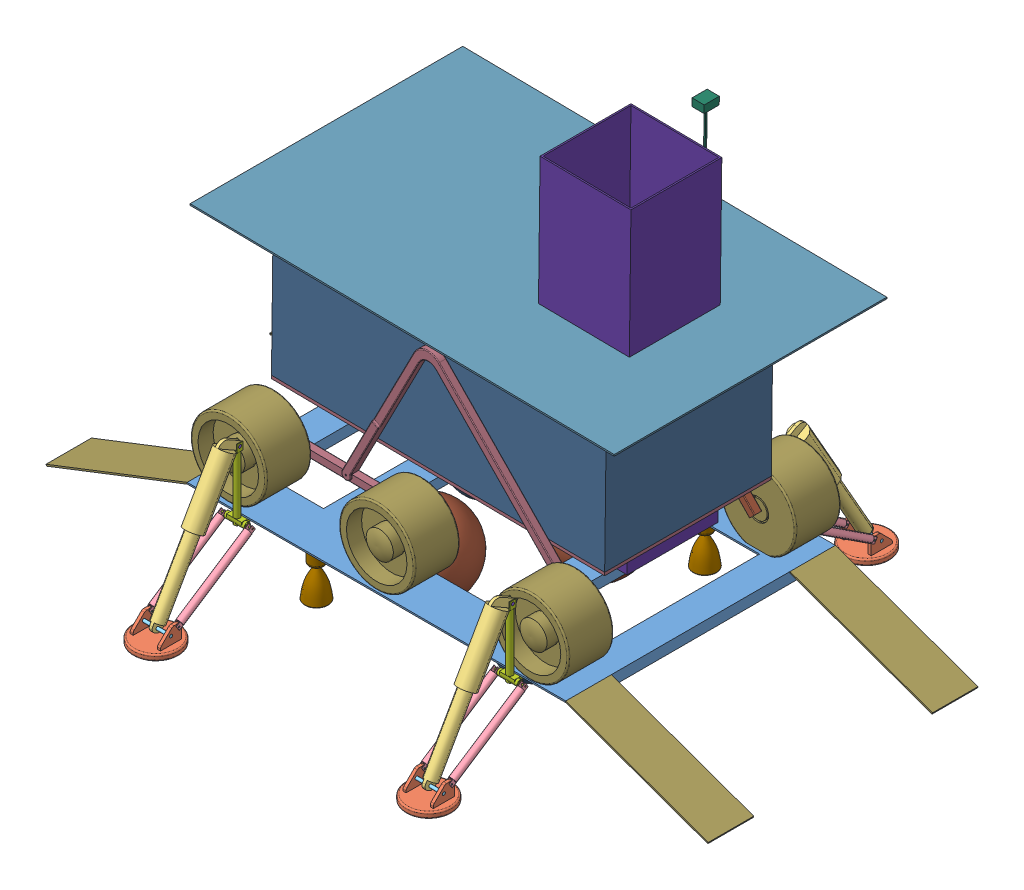
SolidWorks assembly Rover Lander assem, configuration Default. Lengths in mm.
Overall size (4376.53 3029.6 3190.9).
97 component instances, 36 part files, 4 mates.
Components (placement in the parent):
- lander_base_assem-1: lander_base_assem [Default] at (-53.6849 8.2156 22.7472) size (4376.53 1074.03 3190.9)
  - Lander base-1: Lander base [Default] at (714.6592 -461.0878 -63.8597) size (2500 70 1780)
  - leg_aluminum_rev-1: leg_aluminum_rev [Default] at (365.8635 -910.6524 482.3383) x (0 0.000985 1) z (-1 0 0) size (725.04 964.3 300)
    - base_leg-1: base_leg [Default] at (9.2435 -7.9699 0.537) size (300 140 300)
    - Main_leg-1: Main_leg [Default] at (-240.1972 521.872 0.537) x (0 0 -1) z (0.869495 0.493942 0) size (120 996.55 163.86)
    - Support_leg-1: Support_leg [Default] at (-74.206 133.9648 -89.463) x (0 0 -1) z (0.548366 0.836238 0) size (45 600 45)
    - leg_pin-1: leg_pin [Default] at (9.2435 82.777 -99.463) x (0 0 1) z (-0.667547 0.744568 0) size (200 20 20)
    - Support_leg-2: Support_leg [Default] at (-74.206 133.9648 90.537) x (0 0 -1) z (0.548366 0.836238 0) size (45 600 45)
    - leg_support_pin-1: leg_support_pin [Default] at (-40.7565 112.0301 -76.463) x (0 0 -1) z (1 0 0) size (26 10 10)
    - leg_support_pin-2: leg_support_pin [Default] at (-40.7565 112.0301 103.537) x (0 0 -1) z (1 0 0) size (26 10 10)
    - leg_joiner-1: leg_joiner [Default] at (-525.7944 410.0826 0.537) x (1 -0.000985 0) z (0 0 1) size (60 470.09 206)
    - leg_joiner_pin-1: leg_joiner_pin [Default] at (-525.3511 860.1724 -19.463) size (20 20 40)
  - leg_aluminum_rev-2: leg_aluminum_rev [Default] at (364.7896 -910.6524 -2390.0576) x (0 0.000985 -1) z (1 0 0) size (725.04 964.3 300)
    - base_leg-1: base_leg [Default] at (9.2435 -7.9699 0.537) size (300 140 300)
    - Main_leg-1: Main_leg [Default] at (-240.1972 521.872 0.537) x (0 0 -1) z (0.869495 0.493942 0) size (120 996.55 163.86)
    - Support_leg-1: Support_leg [Default] at (-74.206 133.9648 -89.463) x (0 0 -1) z (0.548366 0.836238 0) size (45 600 45)
    - leg_pin-1: leg_pin [Default] at (9.2435 82.777 -99.463) x (0 0 1) z (-0.667547 0.744568 0) size (200 20 20)
    - Support_leg-2: Support_leg [Default] at (-74.206 133.9648 90.537) x (0 0 -1) z (0.548366 0.836238 0) size (45 600 45)
    - leg_support_pin-1: leg_support_pin [Default] at (-40.7565 112.0301 -76.463) x (0 0 -1) z (1 0 0) size (26 10 10)
    - leg_support_pin-2: leg_support_pin [Default] at (-40.7565 112.0301 103.537) x (0 0 -1) z (1 0 0) size (26 10 10)
    - leg_joiner-1: leg_joiner [Default] at (-525.7944 410.0826 0.537) x (1 -0.000985 0) z (0 0 1) size (60 470.09 206)
    - leg_joiner_pin-1: leg_joiner_pin [Default] at (-525.3511 860.1724 -19.463) size (20 20 40)
  - leg_aluminum_rev-3: leg_aluminum_rev [Default] at (-1436.5452 -910.6524 -2390.0576) x (0 0.000985 -1) z (1 0 0) size (725.04 964.3 300)
    - base_leg-1: base_leg [Default] at (9.2435 -7.9699 0.537) size (300 140 300)
    - Main_leg-1: Main_leg [Default] at (-240.1972 521.872 0.537) x (0 0 -1) z (0.869495 0.493942 0) size (120 996.55 163.86)
    - Support_leg-1: Support_leg [Default] at (-74.206 133.9648 -89.463) x (0 0 -1) z (0.548366 0.836238 0) size (45 600 45)
    - leg_pin-1: leg_pin [Default] at (9.2435 82.777 -99.463) x (0 0 1) z (-0.667547 0.744568 0) size (200 20 20)
    - Support_leg-2: Support_leg [Default] at (-74.206 133.9648 90.537) x (0 0 -1) z (0.548366 0.836238 0) size (45 600 45)
    - leg_support_pin-1: leg_support_pin [Default] at (-40.7565 112.0301 -76.463) x (0 0 -1) z (1 0 0) size (26 10 10)
    - leg_support_pin-2: leg_support_pin [Default] at (-40.7565 112.0301 103.537) x (0 0 -1) z (1 0 0) size (26 10 10)
    - leg_joiner-1: leg_joiner [Default] at (-525.7944 410.0826 0.537) x (1 -0.000985 0) z (0 0 1) size (60 470.09 206)
    - leg_joiner_pin-1: leg_joiner_pin [Default] at (-525.3511 860.1724 -19.463) size (20 20 40)
  - leg_aluminum_rev-4: leg_aluminum_rev [Default] at (-1435.4713 -910.6524 482.3383) x (0 0.000985 1) z (-1 0 0) size (725.04 964.3 300)
    - base_leg-1: base_leg [Default] at (9.2435 -7.9699 0.537) size (300 140 300)
    - Main_leg-1: Main_leg [Default] at (-240.1972 521.872 0.537) x (0 0 -1) z (0.869495 0.493942 0) size (120 996.55 163.86)
    - Support_leg-1: Support_leg [Default] at (-74.206 133.9648 -89.463) x (0 0 -1) z (0.548366 0.836238 0) size (45 600 45)
    - leg_pin-1: leg_pin [Default] at (9.2435 82.777 -99.463) x (0 0 1) z (-0.667547 0.744568 0) size (200 20 20)
    - Support_leg-2: Support_leg [Default] at (-74.206 133.9648 90.537) x (0 0 -1) z (0.548366 0.836238 0) size (45 600 45)
    - leg_support_pin-1: leg_support_pin [Default] at (-40.7565 112.0301 -76.463) x (0 0 -1) z (1 0 0) size (26 10 10)
    - leg_support_pin-2: leg_support_pin [Default] at (-40.7565 112.0301 103.537) x (0 0 -1) z (1 0 0) size (26 10 10)
    - leg_joiner-1: leg_joiner [Default] at (-525.7944 410.0826 0.537) x (1 -0.000985 0) z (0 0 1) size (60 470.09 206)
    - leg_joiner_pin-1: leg_joiner_pin [Default] at (-525.3511 860.1724 -19.463) size (20 20 40)
  - MR_80b-1: MR_80b [Default] at (-1081.6322 -841.0878 -214.0715) size (153.97 380 153.97)
  - MR_80b-2: MR_80b [Default] at (16.7233 -838.4394 -1679.7382) x (0.999992 0 0.004071) z (-0.004071 0 0.999992) size (153.97 380 153.97)
  - Helium_tank-1: Helium_tank [Default] at (203.1711 -638.5192 -541.9795) x (0.94256 0.329358 0.055716) z (0.325345 -0.942975 0.070353) size (400 400 400)
  - Helium_tank-2: Helium_tank [Default] at (-953.3371 -635.4687 -1361.8199) x (0.977489 0.124684 0.170201) z (-0.107578 -0.399417 0.910436) size (400 400 400)
  - Hydrazine_tank-1: Hydrazine_tank [Default] at (-643.5463 -334.2768 -539.5578) x (0.363071 0.900077 0.240916) z (0.071543 0.230867 -0.970352) size (550 550 550)
  - Hydrazine_tank-2: Hydrazine_tank [Default] at (-75.2899 -529.4709 -1409.1331) x (0.901296 0.217178 -0.374832) z (0.418463 -0.660267 0.623647) size (550 550 550)
  - ramp-1: ramp [Default] at (-1781.7966 -460.4387 -1543.8597) x (0.935086 0.354421 0) z (0 0 1) size (1000 10 300)
  - ramp-2: ramp [Default] at (-1781.7155 -460.4076 -63.8597) x (0.931973 0.362527 0) z (0 0 1) size (1000 10 300)
  - ramp-3: ramp [Default] at (1652.7267 -797.6846 -1543.8597) x (0.941439 -0.337182 0) z (0 0 1) size (1000 10 300)
  - ramp-4: ramp [Default] at (1652.3714 -798.6446 -63.8597) x (0.941094 -0.338146 0) z (0 0 1) size (1000 10 300)
- layout_Assem_with_cover-1: layout_Assem_with_cover [Default] at (-567.9998 65.7276 -953.5275) x (0.999924 -0.012312 0) z (0 0 1) size (2907.8 2551.43 1996.55)
  - Rover_base-1: Rover_base [Default] at (-1064.6676 -0.8898 562.4151) size (2200 20 1100)
  - Neutron_spectrometer-1: Neutron_spectrometer [Default] at (-926.7762 19.1102 412.2415) size (300 57 300)
  - Neutron_spectrometer_electronics-1: Neutron_spectrometer_electronics [Default] at (-664.5809 19.1102 526.5713) size (180 30 130)
  - gc-1: gc [Default] at (-1085.6976 19.1102 139.436) size (100 80 100)
  - svr_box-1: svr_box [Default] at (435.3324 -172.8625 312.4151) size (600 2100 600)
  - xrf-1: xrf [Default] at (-1008.6936 19.1102 -66.8918) size (80 90 80)
  - geotechnical_exp-1: geotechnical_exp [Default] at (118.8439 19.1102 479.7148) x (0.999975 0 -0.007135) z (0.007135 0 0.999975) size (130 30 130)
  - penetrometer_3-1: penetrometer_3 [Default] at (989.1282 19.1102 -518.5473) x (-0.60186 0 0.798602) z (-0.798602 0 -0.60186) size (20 40 20)
  - penetrometer_3-2: penetrometer_3 [Default] at (934.1975 19.1102 -522.9905) size (20 40 20)
  - penetrometer_3-3: penetrometer_3 [Default] at (890.3988 19.1102 -523.0172) x (0.957231 0 -0.289323) z (0.289323 0 0.957231) size (20 40 20)
  - power-1: power [Default] at (-535.812 19.1102 343.3407) size (180 90 96)
  - geotechnical_exp_vane-1: geotechnical_exp_vane [Default] at (965.2252 19.1102 444.9326) size (220 40 220)
  - Magnents-1: Magnents [Default] at (-1020.4169 -10.8898 98.2252) size (45 10 45)
  - Becon-1: Becon [Default] at (656.9367 19.1102 515.9957) size (80 90 100)
  - Belly Cam-1: Belly Cam [Default] at (-660.0101 -90.1314 99.1462) size (150 100 150)
  - power_tank-1: power_tank [Default] at (-887.862 555.3324 -63.369) x (-0.812429 0.027314 0.58242) z (0.582091 -0.01957 0.812888) size (1560.46 846.95 1367.46)
    - power_tank_10-1: power_tank_10 [Default] at (-67.1815 281.3265 414.5148) size (500 500 500)
    - power_tank_10-2: power_tank_10 [Default] at (-251.8267 476.4977 723.0274) x (0.786037 -0.315714 0.53148) z (0.083274 0.905991 0.415025) size (500 500 500)
    - power_tank_10-3: power_tank_10 [Default] at (-733.4982 325.3571 380.2859) x (0.665484 -0.133715 0.734337) z (-0.678573 0.301428 0.669836) size (500 500 500)
    - power_tank_10-4: power_tank_10 [Default] at (-1034.3616 424.6302 664.9742) x (0.724325 0.588989 -0.358392) z (-0.233278 0.698521 0.676499) size (500 500 500)
    - power_tank_10-5: power_tank_10 [Default] at (-695.3433 297.5492 1147.5051) x (0.994968 0.097333 0.023775) z (-0.042044 0.190197 0.980845) size (500 500 500)
  - Tank_seperator_plate-1: Tank_seperator_plate [Default] at (435.3324 529.1102 512.4151) size (1500 10 1000)
  - power_tank-3: power_tank [Default] at (-887.862 502.888 93.4377) x (-0.812429 -0.027314 -0.58242) z (0.582091 0.01957 -0.812888) size (1560.46 846.95 1367.46)
    - power_tank_10-1: power_tank_10 [Default] at (-67.1815 281.3265 414.5148) size (500 500 500)
    - power_tank_10-2: power_tank_10 [Default] at (-251.8267 476.4977 723.0274) x (0.786037 -0.315714 0.53148) z (0.083274 0.905991 0.415025) size (500 500 500)
    - power_tank_10-3: power_tank_10 [Default] at (-733.4982 325.3571 380.2859) x (0.665484 -0.133715 0.734337) z (-0.678573 0.301428 0.669836) size (500 500 500)
    - power_tank_10-4: power_tank_10 [Default] at (-1034.3616 424.6302 664.9742) x (0.724325 0.588989 -0.358392) z (-0.233278 0.698521 0.676499) size (500 500 500)
    - power_tank_10-5: power_tank_10 [Default] at (-695.3433 297.5492 1147.5051) x (0.994968 0.097333 0.023775) z (-0.042044 0.190197 0.980845) size (500 500 500)
  - Rover_base_cover-1: Rover_base_cover [Default] at (1135.3324 1069.1102 -537.5849) x (1 0 0) z (0 0 -1) size (2200 1050 1100)
  - left_mobiiity_assemSLDASM-1: left_mobiiity_assemSLDASM [Default] at (483.248 -113.7012 -588.2789) x (-1 0 0) z (0 0 -1) size (2699.35 1341.14 400.39)
    - Suspension arms-1: Suspension arms [Default] at (-510.2208 -182.1885 -50.694) size (2035.36 1012.73 130)
    - wheel-1: wheel [Default] at (-515.577 -152.6706 299.306) x (-0.792605 -0.609735 0) z (0 0 -1) size (500 500 300.39)
    - wheel-2: wheel [Default] at (1479.7792 -157.1885 299.306) x (-0.72713 -0.6865 0) z (0 0 -1) size (500 500 300.39)
    - wheel-3: wheel [Default] at (499.7792 -157.1885 299.306) x (-0.949229 -0.314586 0) z (0 0 -1) size (500 500 300.39)
  - right_mobiiity_assemSLDASM-1: right_mobiiity_assemSLDASM [Default] at (657.788 -311.6325 815.2315) x (-1 0 0) z (0 0 -1) size (2495.36 1237.73 400.39)
    - Suspension arms_mirror-1: Suspension arms_mirror [Default] at (-335.6808 35.7938 152.8164) size (2035.36 1012.73 130)
    - wheel-1: wheel [Default] at (1654.3192 60.7938 -97.1836) size (500 500 300.39)
    - wheel-2: wheel [Default] at (-341.0371 65.3118 -97.1836) size (500 500 300.39)
    - wheel-3: wheel [Default] at (674.3192 60.7938 -97.1836) size (500 500 300.39)
  - solar cell-1: solar cell [Default] at (-1264.6676 1069.1102 -887.5849) x (-1 0 0) z (0 0 -1) size (2800 10 1800)
  - stero_imaging_sys-2: stero_imaging_sys [Default] at (325.3324 1059.1102 -537.5849) size (80 548.91 402.36)
  - arm-1: arm [Default] at (-1301.9354 19.1102 -517.5849) x (-1 0 0) z (0 0 -1) size (1100 100 100)
  - drill-1: drill [Default] at (-665.3253 539.1102 -237.5849) size (500 200 250)
  - scoop-1: scoop [Default] at (-1325.6367 25.0847 -517.5849) x (-0.755278 0.655405 0) z (0.655405 0.755278 0) size (211.36 101.82 100)
Mates (geometry in assembly coordinates):
- Tangent1: tangent anti-aligned: plane of lander_base_assem-1/Lander base-1 through (660.9743 -442.8722 -41.1125) normal (0 1 0); cylinder of layout_Assem_with_cover-1/left_mobiiity_assemSLDASM-1/wheel-2
- Tangent2: tangent anti-aligned: plane of lander_base_assem-1/Lander base-1 through (660.9743 -442.8722 -41.1125) normal (0 1 0); cylinder of layout_Assem_with_cover-1/right_mobiiity_assemSLDASM-1/wheel-2
- Coincident1: coincident aligned: plane of lander_base_assem-1/Lander base-1 through (660.9743 -442.8722 -41.1125) normal (0 0 1); plane of layout_Assem_with_cover-1/right_mobiiity_assemSLDASM-1/wheel-1 through (-1567.5438 -172.8227 -41.1125) normal (0 0 1)
- Distance2: distance = 200 mm: line of lander_base_assem-1/Lander base-1; plane of layout_Assem_with_cover-1/Rover_base_cover-1 through (-1632.3514 97.9447 -1491.1125) normal (-0.999924 0.012312 0)
